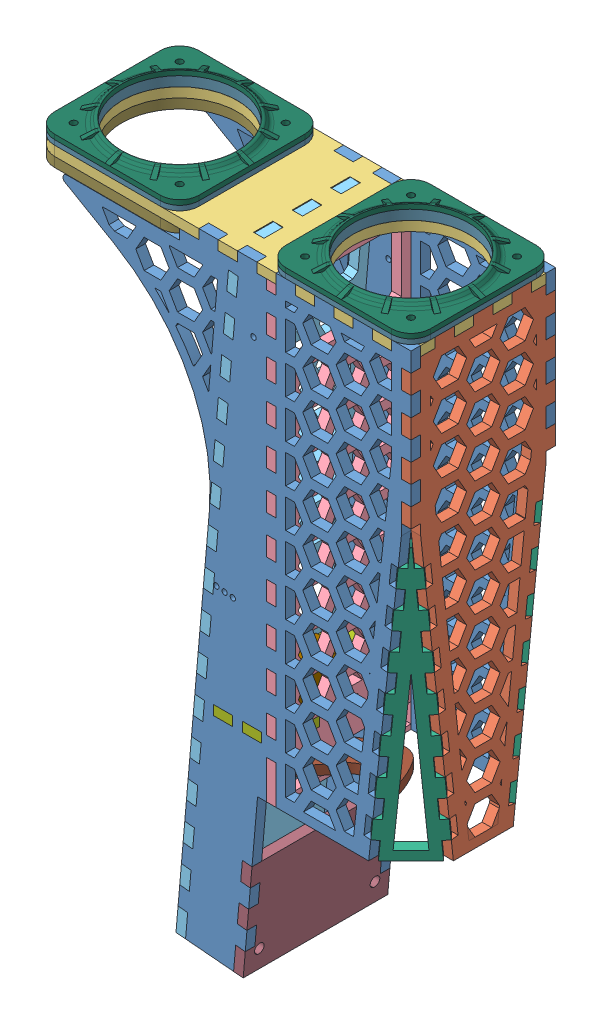
SolidWorks assembly Dispenser Assembly, configuration Default. Lengths in mm.
Overall size (257.34 422.48 114.62).
20 component instances, 15 part files, 45 mates.
Components (placement in the parent):
- Dispenser Side-1: Dispenser Side [Default] at (86.2541 40.0661 209.2088) size (229.27 412.41 6.35)
- Dispenser Side-2: Dispenser Side [Default] at (86.2541 40.0661 298.1088) size (229.27 412.41 6.35)
- Dispenser Back-1: Dispenser Back [Default] at (231.9768 40.0661 209.2088) x (0 0 1) z (-1 0 0) size (95.25 304.8 6.35)
- Dispenser Top-1: Dispenser Top [Default] at (231.9768 338.5161 304.4588) x (0 0 -1) z (1 0 0) size (95.25 6.35 247.65)
- Dispenser Inside-1: Dispenser Inside [Default] at (143.0768 40.0661 209.2088) x (0 0 1) z (-1 0 0) size (95.25 304.8 6.35)
- Dispenser Front-1: Dispenser Front [Default] at (92.58 39.5127 209.2088) x (0 0 1) z (-0.996195 0.087156 0) size (95.25 410.65 6.35)
- Dispenser Back Angle-1: Dispenser Back Angle [Default] at (199.6021 40.5578 299.9821) x (0.707107 0 -0.707107) z (0.704984 -0.077432 0.704984) size (37.49 189.58 6.35)
- Dispenser Back Angle-2: Dispenser Back Angle [Default] at (204.0787 40.0661 209.2088) x (0.707107 0 0.707107) z (-0.704984 0.077432 0.704984) size (37.49 189.58 6.35)
- Dispenser Bottom-1: Dispenser Bottom [Default] at (86.2541 40.0661 209.2088) x (0 0 1) z (-1 0 0) size (95.25 6.35 53.49)
- Tetrix Servo 180° (with Horn)-4: Tetrix Servo 180° (with Horn) [Default] at (143.1518 72.543 274.1079) x (-1 0 0) z (0 0 1) size (22 47.52 56.6)
  - Tetrix Servo Body Screw B-1: Tetrix Servo Body Screw B [Default] at (19.125 20.2268 4.9509) size (5.08 10.95 5.08)
  - Tetrix Servo Body B-1: Tetrix Servo Body B [Default] at (19.125 0.7268 4.9509) size (20 43.2 56.6)
  - Tetrix Servo Horn B-1: Tetrix Servo Horn B [Default] at (19.125 18.2268 4.9509) size (22 6.2 22)
- Dispenser Latch-2: Dispenser Latch [Default] at (124.0268 52.3161 279.0588) x (-0.008189 0 -0.999966) z (-0.999966 0 0.008189) size (55.08 6.35 76.2)
- Tube End Plate-3: Tube End Plate [Default] at (31.9518 332.1661 256.8338) x (-1 0 0) z (0 0 -1) size (95.25 6.35 95.25)
- Dispenser Bottom Back-2: Dispenser Bottom Back [Default] at (130.535 36.192 209.2088) x (0 0 1) z (-0.996195 0.087156 0) size (95.25 66.58 6.35)
- Tube Clamp Plate A-1: Tube Clamp Plate A [Default] at (184.3518 344.8661 256.8338) x (1 0 0) z (0 1 0) size (95.25 95.25 6.35)
- Tube Clamp Plate A-2: Tube Clamp Plate A [Default] at (31.9518 344.8661 256.8338) x (1 0 0) z (0 1 0) size (95.25 95.25 6.35)
- Tube Clamp Plate B-1: Tube Clamp Plate B [Default] at (184.3518 344.8661 256.8338) x (1 0 0) z (0 1 0) size (95.25 95.25 6.35)
- Tube Clamp Plate B-2: Tube Clamp Plate B [Default] at (31.9518 344.8661 256.8338) x (1 0 0) z (0 1 0) size (95.25 95.25 6.35)
Mates (geometry in assembly coordinates):
- Coincident14: coincident aligned: plane of Dispenser Side-1 through (86.2541 40.0661 215.5588) normal (-0.996195 0.087156 0); plane of Dispenser Front-1 through (86.2541 40.0661 209.2088) normal (-0.996195 0.087156 0)
- Coincident22: coincident aligned: plane of Dispenser Side-1 through (86.2541 344.8661 215.5588) normal (0 1 0); plane of Dispenser Side-2 through (86.2541 344.8661 304.4588) normal (0 1 0)
- Coincident55: coincident: plane of Dispenser Top-1 through (231.9768 344.8661 304.4588) normal (0 1 0); line of Dispenser Front-1 through (112.9207 344.8661 263.1838) axis (0 0 -1)
- Distance2: distance = 31.75 mm aligned: plane of Dispenser Bottom-1 through (89.5875 71.8161 304.4588) normal (0 -1 0); plane of Dispenser Side-2 through (86.2541 40.0661 304.4588) normal (0 -1 0)
- Coincident80: coincident anti-aligned: plane of Dispenser Bottom-1 through (89.5875 71.8161 304.4588) normal (0 -1 0); plane of Tetrix Servo 180° (with Horn)-4/Tetrix Servo Body B-1 through (131.9018 71.8161 294.1588) normal (0 1 0)
- Concentric3: concentric aligned: cylinder of Dispenser Bottom-1 through (119.0268 71.8161 293.0588) axis (0 1 0) radius 1.75; cylinder of Tetrix Servo 180° (with Horn)-4/Tetrix Servo Body B-1 through (119.0268 69.3161 293.0588) axis (0 1 0) radius 2.15
- Concentric4: concentric aligned: cylinder of Dispenser Bottom-1 through (129.0268 71.8161 245.0588) axis (0 1 0) radius 1.75; cylinder of Tetrix Servo 180° (with Horn)-4/Tetrix Servo Body B-1 through (129.0268 69.3161 245.0588) axis (0 1 0) radius 2.15
- Concentric6: concentric anti-aligned: cylinder of Tetrix Servo 180° (with Horn)-4/Tetrix Servo Horn B-1 through (124.0268 54.3161 279.0588) axis (0 -1 0) radius 11; cylinder of Dispenser Latch-2 through (124.0268 45.9661 279.0588) axis (0 1 0) radius 3.175
- Coincident81: coincident anti-aligned: plane of Tetrix Servo 180° (with Horn)-4/Tetrix Servo Horn B-1 through (124.0268 52.3161 279.0588) normal (0 -1 0); plane of Dispenser Latch-2 through (124.0268 52.3161 279.0588) normal (0 1 0)
- Coincident85: coincident aligned: plane of Dispenser Side-2 through (86.2541 40.0661 304.4588) normal (0 0 1); plane of Dispenser Front-1 through (86.2541 40.0661 304.4588) normal (0 0 1)
- Coincident86: coincident aligned: plane of Dispenser Side-2 through (86.2541 40.0661 304.4588) normal (0 0 1); plane of Dispenser Top-1 through (231.9768 344.8661 304.4588) normal (0 0 1)
- Coincident87: coincident aligned: plane of Dispenser Side-1 through (86.2541 40.0661 209.2088) normal (0 0 -1); plane of Dispenser Top-1 through (231.9768 344.8661 209.2088) normal (0 0 -1)
- Coincident91: coincident anti-aligned: plane of Dispenser Side-2 through (205.4653 52.6902 298.1088) normal (0.109178 0.994022 0); plane of Dispenser Back Angle-1 through (200.9886 53.1819 299.9821) normal (-0.109178 -0.994022 0)
- Coincident92: coincident aligned: line of Dispenser Side-1 through (205.4653 52.6902 209.2088) axis (-0.109178 -0.994022 0); line of Dispenser Back Angle-2 through (206.8518 65.3143 209.2088) axis (-0.109178 -0.994022 0)
- Coincident94: coincident anti-aligned: plane of Dispenser Top-1 through (231.9768 338.5161 304.4588) normal (0 -1 0); plane of Tube End Plate-3 through (31.9518 338.5161 256.8338) normal (0 1 0)
- Coincident95: coincident aligned: plane of Dispenser Top-1 through (231.9768 344.8661 304.4588) normal (0 0 1); plane of Tube End Plate-3 through (-15.6732 338.5161 304.4588) normal (0 0 1)
- Coincident96: coincident aligned: plane of Dispenser Top-1 through (-15.6732 344.8661 304.4588) normal (-1 0 0); plane of Tube End Plate-3 through (-15.6732 338.5161 209.2088) normal (-1 0 0)
- Coincident97: coincident aligned: plane of Dispenser Side-2 through (231.9768 40.0661 304.4588) normal (1 0 0); plane of Dispenser Back-1 through (231.9768 40.0661 209.2088) normal (1 0 0)
- Coincident98: coincident aligned: plane of Dispenser Side-2 through (86.2541 40.0661 304.4588) normal (0 0 1); plane of Dispenser Back-1 through (225.6268 40.0661 304.4588) normal (0 0 1)
- Coincident99: coincident aligned: plane of Dispenser Side-2 through (86.2541 344.8661 304.4588) normal (0 1 0); plane of Dispenser Back-1 through (225.6268 344.8661 209.2088) normal (0 1 0)
- Coincident100: coincident aligned: plane of Dispenser Back-1 through (231.9768 40.0661 209.2088) normal (1 0 0); plane of Dispenser Top-1 through (231.9768 344.8661 304.4588) normal (1 0 0)
- Coincident103: coincident aligned: plane of Dispenser Side-2 through (86.2541 40.0661 304.4588) normal (0 0 1); plane of Dispenser Bottom-1 through (86.2541 40.0661 304.4588) normal (0 0 1)
- Coincident104: coincident aligned: plane of Dispenser Side-2 through (86.2541 40.0661 304.4588) normal (-0.996195 0.087156 0); plane of Dispenser Front-1 through (86.2541 40.0661 209.2088) normal (-0.996195 0.087156 0)
- Coincident106: coincident anti-aligned: line of Dispenser Back-1 through (231.9768 52.6902 277.9473) axis (0 -0.994022 -0.109178); line of Dispenser Back Angle-1 through (231.9768 52.6902 277.9473) axis (0 0.994022 0.109178)
- Coincident107: coincident aligned: line of Dispenser Back-1 through (231.9768 40.0661 237.1069) axis (0 0.994022 -0.109178); line of Dispenser Back Angle-2 through (231.9768 52.6902 235.7203) axis (0 0.994022 -0.109178)
- Coincident108: coincident anti-aligned: plane of Dispenser Side-1 through (143.0768 319.4661 209.2088) normal (-1 0 0); plane of Dispenser Inside-1 through (143.0768 40.0661 209.2088) normal (1 0 0)
- Coincident109: coincident aligned: plane of Dispenser Side-1 through (86.2541 40.0661 209.2088) normal (0 0 -1); plane of Dispenser Inside-1 through (136.7268 40.0661 209.2088) normal (0 0 -1)
- Coincident110: coincident aligned: plane of Dispenser Top-1 through (231.9768 344.8661 304.4588) normal (0 1 0); plane of Dispenser Inside-1 through (136.7268 344.8661 209.2088) normal (0 1 0)
- Coincident111: coincident aligned: plane of Dispenser Inside-1 through (143.0768 40.0661 209.2088) normal (1 0 0); plane of Dispenser Bottom-1 through (143.0768 71.8161 304.4588) normal (1 0 0)
- Coincident112: coincident aligned: plane of Dispenser Side-2 through (86.2541 344.8661 304.4588) normal (0 1 0); plane of Dispenser Top-1 through (231.9768 344.8661 304.4588) normal (0 1 0)
- Coincident113: coincident anti-aligned: plane of Dispenser Side-2 through (120.8885 -1.2095 298.1088) normal (0.996195 -0.087156 0); plane of Dispenser Bottom Back-2 through (124.2092 36.7455 209.2088) normal (-0.996195 0.087156 0)
- Coincident114: coincident aligned: plane of Dispenser Side-2 through (86.2541 40.0661 304.4588) normal (0 0 1); plane of Dispenser Bottom Back-2 through (124.2092 36.7455 304.4588) normal (0 0 1)
- Coincident115: coincident aligned: plane of Dispenser Side-2 through (77.1303 -64.2193 298.1088) normal (-0.087156 -0.996195 0); plane of Dispenser Bottom Back-2 through (121.4112 -68.0934 209.2088) normal (-0.087156 -0.996195 0)
- Coincident116: coincident anti-aligned: plane of Dispenser Top-1 through (231.9768 344.8661 304.4588) normal (0 1 0); plane of Tube Clamp Plate A-1 through (184.3518 344.8661 256.8338) normal (0 -1 0)
- Coincident117: coincident anti-aligned: plane of Dispenser Top-1 through (231.9768 344.8661 304.4588) normal (0 1 0); plane of Tube Clamp Plate A-2 through (31.9518 344.8661 256.8338) normal (0 -1 0)
- Coincident118: coincident aligned: plane of Dispenser Side-2 through (86.2541 40.0661 304.4588) normal (0 0 1); plane of Tube Clamp Plate A-2 through (79.5768 348.0411 304.4588) normal (0 0 1)
- Coincident119: coincident aligned: plane of Dispenser Side-2 through (86.2541 40.0661 304.4588) normal (0 0 1); plane of Tube Clamp Plate A-1 through (231.9768 348.0411 304.4588) normal (0 0 1)
- Concentric7: concentric anti-aligned: cylinder of Dispenser Top-1 through (184.3518 338.5161 256.8338) axis (0 1 0) radius 38.1; cylinder of Tube Clamp Plate A-1 through (184.3518 348.0411 256.8338) axis (0 -1 0) radius 38.1
- Concentric8: concentric anti-aligned: cylinder of Dispenser Top-1 through (31.9518 338.5161 256.8338) axis (0 1 0) radius 38.1; cylinder of Tube Clamp Plate A-2 through (31.9518 348.0411 256.8338) axis (0 -1 0) radius 38.1
- Coincident121: coincident aligned: plane of Tube Clamp Plate A-1 through (231.9768 348.0411 304.4588) normal (0 0 1); plane of Tube Clamp Plate B-1 through (231.9768 348.0411 304.4588) normal (0 0 1)
- Concentric9: concentric aligned: cylinder of Tube Clamp Plate A-1 through (184.3518 348.0411 256.8338) axis (0 -1 0) radius 38.1; cylinder of Tube Clamp Plate B-1 through (184.3518 348.0411 256.8338) axis (0 -1 0) radius 38.1
- Coincident123: coincident aligned: plane of Tube Clamp Plate A-2 through (79.5768 348.0411 304.4588) normal (0 0 1); plane of Tube Clamp Plate B-2 through (79.5768 348.0411 304.4588) normal (0 0 1)
- Concentric10: concentric aligned: cylinder of Tube Clamp Plate A-2 through (31.9518 348.0411 256.8338) axis (0 -1 0) radius 38.1; cylinder of Tube Clamp Plate B-2 through (31.9518 348.0411 256.8338) axis (0 -1 0) radius 38.1
- Coincident124: coincident anti-aligned: plane of Tube Clamp Plate A-2 through (31.9518 348.0411 256.8338) normal (0 1 0); plane of Tube Clamp Plate B-2 through (31.9518 348.0411 256.8338) normal (0 -1 0)
- Coincident125: coincident anti-aligned: plane of Tube Clamp Plate A-1 through (184.3518 348.0411 256.8338) normal (0 1 0); plane of Tube Clamp Plate B-1 through (184.3518 348.0411 256.8338) normal (0 -1 0)
